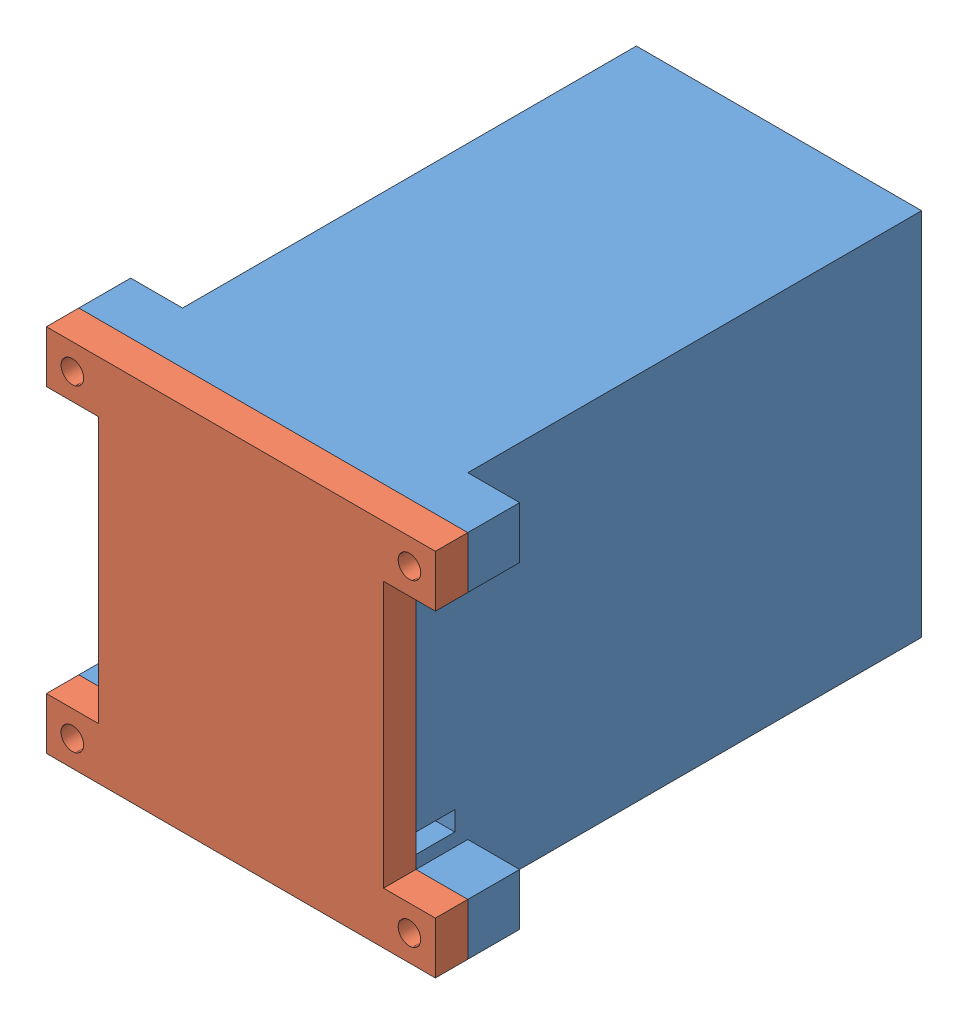
SolidWorks assembly battery_box_14V8, configuration 預設. Lengths in mm.
Overall size (60 57 83).
3 component instances, 3 part files, 5 mates.
Components (placement in the parent):
- battery_box_14V8-1: battery_box_14V8 [預設] at (17.6895 -40.9203 78) size (60 57 78)
- battery_cap_14V8-1: battery_cap_14V8 [預設] at (17.6895 -12.4203 117) size (60 57 5)
- battery14_8Vmodel-1: battery14_8Vmodel [預設] at (17.6895 -8.9203 78) x (0 0 1) z (0 -1 0) size (75 38 44)
Mates (geometry in assembly coordinates):
- 同軸心1: concentric anti-aligned: cylinder of battery_box_14V8-1 through (43.6895 12.0797 109) axis (0 0 1) radius 1.75; cylinder of battery_cap_14V8-1 through (43.6895 12.0797 122) axis (0 0 -1) radius 1.75
- 重合/共線/共點1: coincident aligned: circle of battery_box_14V8-1; circle of battery_cap_14V8-1
- 重合/共線/共點2: coincident anti-aligned: plane of battery_box_14V8-1 through (-1.3105 16.0797 39) normal (1 0 0); plane of battery14_8Vmodel-1 through (-1.3105 -30.9203 42) normal (-1 0 0)
- 重合/共線/共點3: coincident anti-aligned: plane of battery_box_14V8-1 through (17.6895 -30.9203 78) normal (0 1 0); plane of battery14_8Vmodel-1 through (17.6895 -30.9203 78) normal (0 -1 0)
- 重合/共線/共點4: coincident anti-aligned: plane of battery_box_14V8-1 through (-4.3105 16.0797 42) normal (0 0 1); plane of battery14_8Vmodel-1 through (-1.3105 -30.9203 42) normal (0 0 -1)
